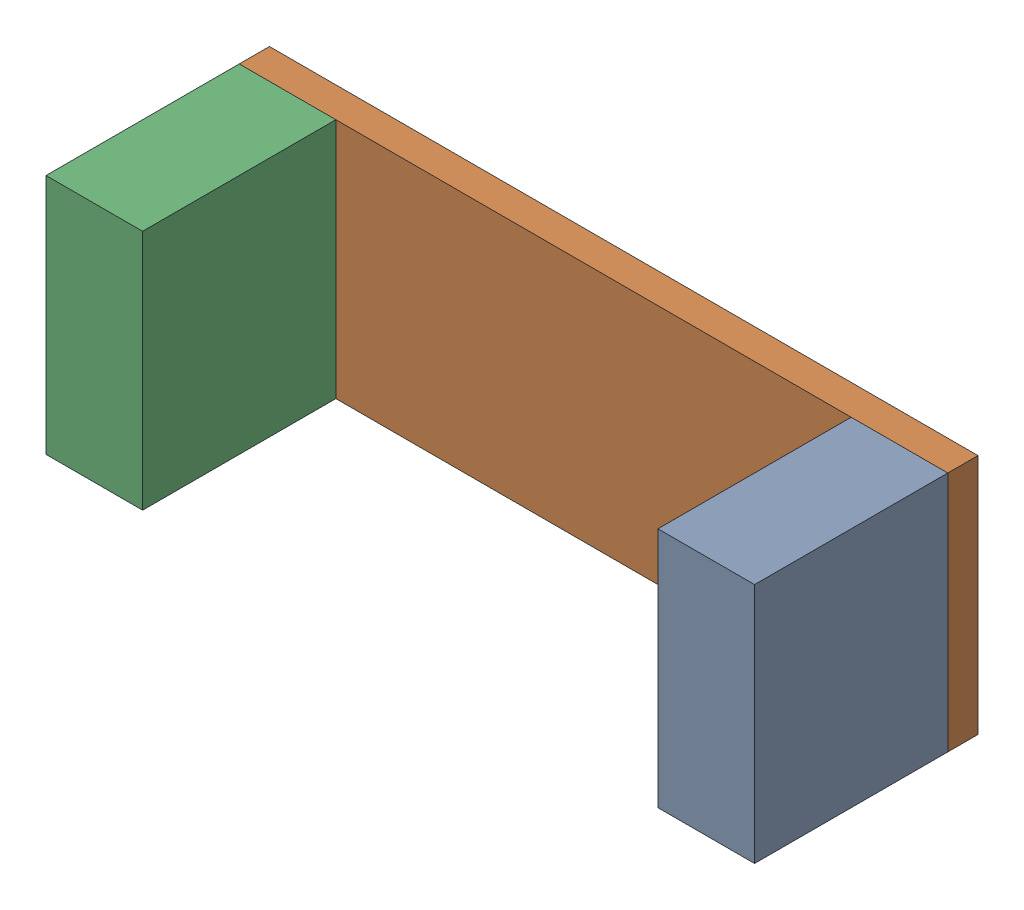
SolidWorks assembly TE-19107-18, configuration Default. Lengths in mm.
Overall size (279.4 95.25 88.11).
3 component instances, 2 part files, 10 mates.
Components (placement in the parent):
- TE-19107-14-2: TE-19107-14 [Default] at (271.7696 47.5704 88.1063) x (1 0 0) z (0 1 0) size (38.1 76.2 95.25)
- TE-19107-15-1: TE-19107-15 [Default] at (134.3246 93.499 0) size (279.4 95.25 11.91)
- TE-19107-14-3: TE-19107-14 [Default] at (30.4696 47.5704 88.1063) x (1 0 0) z (0 1 0) size (38.1 76.2 95.25)
Mates (geometry in assembly coordinates):
- Coincident4: coincident: plane of ?; plane of ? through (134.3246 56.9321 64.0189) normal (0 0 1)
- Coincident5: coincident: unknown of ?; plane of ? through (30.4696 106.2535 64.0189) normal (0 1 0)
- Coincident6: coincident: plane of TE-19107-14-2 through (309.8696 142.8204 88.1063) normal (1 0 0); plane of TE-19107-15-1 through (309.8696 142.8204 11.9062) normal (1 0 0)
- Coincident7: coincident: plane of TE-19107-14-2 through (271.7696 142.8204 11.9062) normal (0 0 -1); plane of TE-19107-15-1 through (134.3246 93.499 11.9062) normal (0 0 1)
- Coincident8: coincident: plane of TE-19107-14-2 through (309.8696 142.8204 88.1063) normal (1 0 0); plane of TE-19107-15-1 through (309.8696 142.8204 11.9062) normal (1 0 0)
- Coincident9: coincident: plane of TE-19107-14-2 through (271.7696 142.8204 88.1063) normal (0 1 0); plane of TE-19107-15-1 through (30.4696 142.8204 11.9062) normal (0 1 0)
- Coincident14: coincident: plane of assembly through (0 0 0) normal (0 0 1); plane of TE-19107-15-1 through (134.3246 93.499 0) normal (0 0 -1); plane of assembly
- Coincident15: coincident: plane of TE-19107-15-1 through (134.3246 93.499 11.9062) normal (0 0 1); plane of ? through (-9.6657 142.8204 11.9062) normal (0 0 -1)
- Coincident16: coincident: plane of TE-19107-15-1 through (30.4696 142.8204 11.9062) normal (0 1 0); plane of ? through (-9.6657 142.8204 88.1063) normal (0 1 0)
- Coincident17: coincident: plane of assembly; plane of assembly; plane of TE-19107-15-1 through (30.4696 142.8204 11.9062) normal (-1 0 0); plane of TE-19107-14-3 through (30.4696 142.8204 88.1063) normal (-1 0 0)
